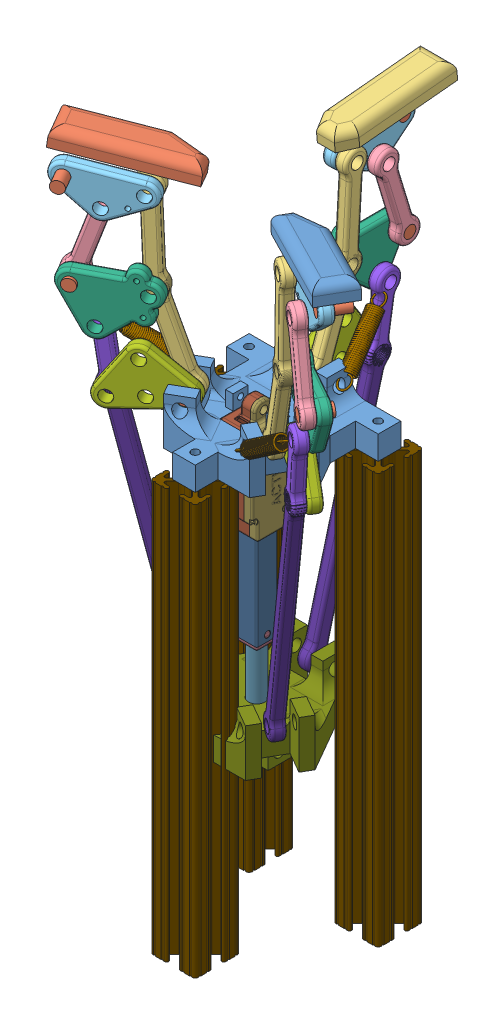
SolidWorks assembly Assem1, configuration Default. Lengths in mm.
Overall size (250.26 371.1 226.62).
54 component instances, 21 part files, 37 mates.
Components (placement in the parent):
- Base-1: Base [Default] at (29.1 37.1493 110.8136) size (84.55 26.4 78.57)
- Finger-1: Finger [Default] at (-55.3683 171.0063 18.6611) x (0.533631 -0.593126 -0.602859) z (-0.629379 -0.754665 0.185375) size (115.18 50.98 104.34)
  - Pin-2: Pin [Default] at (-28.0516 131.9417 56.9365) x (-0.391776 -0.247873 -0.886042) z (-0.883938 -0.165793 0.437227) size (6.6 14.85 6.6)
  - Pin-5: Pin [Default] at (35.7349 149.8083 61.935) x (0.798245 0.298021 0.523439) z (0.545563 0.010572 -0.838003) size (6.6 14.85 6.6)
  - 7.3mmLink-1: 7.3mmLink [Default] at (4.3719 127.2835 41.7035) x (0.803295 0.298106 0.515607) z (0.5381 0.007794 -0.842845) size (61.38 6.6 13.2)
  - 6mmLink-3: 6mmLink [Default] at (-36.8945 113.7346 26.1461) x (0.325014 0.234869 0.91608) z (0.910604 0.183752 -0.370183) size (53.43 6.6 13.2)
  - 7.3mmLink-2: 7.3mmLink [Default] at (-26.5117 113.5278 7.6718) x (0.61862 0.283769 0.732656) z (0.743064 0.091669 -0.662913) size (61.38 6.6 13.2)
  - TriLink3-3: TriLink3 [Default] at (-38.0213 120.0229 24.1342) x (0.965908 0.258866 0.003339) z (0.043091 -0.148042 -0.988042) size (41.14 6.6 31.73)
  - TriLink2-6: TriLink2 [Default] at (-5.9664 136.3894 72.3925) x (0.88404 0.294986 0.362569) z (0.391545 -0.04372 -0.91912) size (35.81 6.6 41.11)
  - TriLink1-5: TriLink1 [Default] at (11.5068 128.7631 61.1059) x (-0.06577 -0.176206 -0.982154) z (0.964629 0.240582 -0.107758) size (37.33 6.6 37.28)
  - Pin-6: Pin [Default] at (-62.2438 123.5843 18.9947) x (0.925135 0.287468 0.247965) z (0.280996 -0.07931 -0.956426) size (6.6 14.85 6.6)
  - 5mmLink-4: 5mmLink [Default] at (-3.3761 129.6337 69.0864) x (0.690224 0.29155 0.662261) z (0.677071 0.062661 -0.733245) size (46.2 6.6 13.2)
  - 9654K127_STEEL EXTENSION SPRING-1: 9654K127_STEEL EXTENSION SPRING [9654K127] at (22.3126 122.661 67.567) size (44.45 7.99 8.44)
- Finger-2: Finger [Default] at (1.5805 170.9978 213.2297) x (-0.790306 -0.59104 -0.161516) z (0.473443 -0.756402 0.45134) size (115.18 50.98 104.34)
  - Pin-2: Pin [Default] at (-28.0516 131.9417 56.9365) x (-0.391776 -0.247873 -0.886042) z (-0.883938 -0.165793 0.437227) size (6.6 14.85 6.6)
  - Pin-5: Pin [Default] at (35.7349 149.8083 61.935) x (0.798245 0.298021 0.523439) z (0.545563 0.010572 -0.838003) size (6.6 14.85 6.6)
  - 7.3mmLink-1: 7.3mmLink [Default] at (4.3719 127.2835 41.7035) x (0.803295 0.298106 0.515607) z (0.5381 0.007794 -0.842845) size (61.38 6.6 13.2)
  - 6mmLink-3: 6mmLink [Default] at (-36.8945 113.7346 26.1461) x (0.325014 0.234869 0.91608) z (0.910604 0.183752 -0.370183) size (53.43 6.6 13.2)
  - 7.3mmLink-2: 7.3mmLink [Default] at (-26.5117 113.5278 7.6718) x (0.61862 0.283769 0.732656) z (0.743064 0.091669 -0.662913) size (61.38 6.6 13.2)
  - TriLink3-3: TriLink3 [Default] at (-38.0213 120.0229 24.1342) x (0.965908 0.258866 0.003339) z (0.043091 -0.148042 -0.988042) size (41.14 6.6 31.73)
  - TriLink2-6: TriLink2 [Default] at (-5.9664 136.3894 72.3925) x (0.88404 0.294986 0.362569) z (0.391545 -0.04372 -0.91912) size (35.81 6.6 41.11)
  - TriLink1-5: TriLink1 [Default] at (11.5068 128.7631 61.1059) x (-0.06577 -0.176206 -0.982154) z (0.964629 0.240582 -0.107758) size (37.33 6.6 37.28)
  - Pin-6: Pin [Default] at (-62.2438 123.5843 18.9947) x (0.925135 0.287468 0.247965) z (0.280996 -0.07931 -0.956426) size (6.6 14.85 6.6)
  - 5mmLink-4: 5mmLink [Default] at (-3.3761 129.6337 69.0864) x (0.690224 0.29155 0.662261) z (0.677071 0.062661 -0.733245) size (46.2 6.6 13.2)
  - 9654K127_STEEL EXTENSION SPRING-1: 9654K127_STEEL EXTENSION SPRING [9654K127] at (22.3126 122.661 67.567) size (44.45 7.99 8.44)
- Finger-3: Finger [Default] at (140.3266 170.905 65.9303) x (0.255276 -0.574797 0.777459) z (0.15415 -0.769619 -0.619616) size (115.18 50.98 104.34)
  - Pin-2: Pin [Default] at (-28.0516 131.9417 56.9365) x (-0.391776 -0.247873 -0.886042) z (-0.883938 -0.165793 0.437227) size (6.6 14.85 6.6)
  - Pin-5: Pin [Default] at (35.7349 149.8083 61.935) x (0.798245 0.298021 0.523439) z (0.545563 0.010572 -0.838003) size (6.6 14.85 6.6)
  - 7.3mmLink-1: 7.3mmLink [Default] at (4.3719 127.2835 41.7035) x (0.803295 0.298106 0.515607) z (0.5381 0.007794 -0.842845) size (61.38 6.6 13.2)
  - 6mmLink-3: 6mmLink [Default] at (-36.8945 113.7346 26.1461) x (0.325014 0.234869 0.91608) z (0.910604 0.183752 -0.370183) size (53.43 6.6 13.2)
  - 7.3mmLink-2: 7.3mmLink [Default] at (-26.5117 113.5278 7.6718) x (0.61862 0.283769 0.732656) z (0.743064 0.091669 -0.662913) size (61.38 6.6 13.2)
  - TriLink3-3: TriLink3 [Default] at (-38.0213 120.0229 24.1342) x (0.965908 0.258866 0.003339) z (0.043091 -0.148042 -0.988042) size (41.14 6.6 31.73)
  - TriLink2-6: TriLink2 [Default] at (-5.9664 136.3894 72.3925) x (0.88404 0.294986 0.362569) z (0.391545 -0.04372 -0.91912) size (35.81 6.6 41.11)
  - TriLink1-5: TriLink1 [Default] at (11.5068 128.7631 61.1059) x (-0.06577 -0.176206 -0.982154) z (0.964629 0.240582 -0.107758) size (37.33 6.6 37.28)
  - Pin-6: Pin [Default] at (-62.2438 123.5843 18.9947) x (0.925135 0.287468 0.247965) z (0.280996 -0.07931 -0.956426) size (6.6 14.85 6.6)
  - 5mmLink-4: 5mmLink [Default] at (-3.3761 129.6337 69.0864) x (0.690224 0.29155 0.662261) z (0.677071 0.062661 -0.733245) size (46.2 6.6 13.2)
  - 9654K127_STEEL EXTENSION SPRING-1: 9654K127_STEEL EXTENSION SPRING [9654K127] at (22.3126 122.661 67.567) size (44.45 7.99 8.44)
- LA1-1: LA1 [Default] at (27.9949 18.3736 107.6457) size (20.03 168.75 20.21) (flexible)
  - EXTENSION_10404_50MM-1: EXTENSION_10404_50MM [Default] at (0.8849 -9.7956 -4.9621) size (12 60 12)
  - CLAMSHELL_BOT_10654-1: CLAMSHELL_BOT_10654 [Default] at (0.8849 36.6044 -13.4621) x (0 0 -1) z (0 -1 0) size (20 14.51 62.21)
  - CLAMSHELL_TOP_10653-1: CLAMSHELL_TOP_10653 [Default] at (0.8849 36.6044 -13.4621) x (0 0 -1) z (0 -1 0) size (20.21 11.32 62)
  - GUIDE_10429-1: GUIDE_10429 [Default] at (0.8849 -71.7956 -4.9621) x (0 0 -1) z (-1 0 0) size (12 7.21 12)
  - SHAFT_10409_50MM2-1: SHAFT_10409_50MM2 [Default] at (0.8849 -57.1489 -4.9621) x (-0.424332 0 0.905507) z (-0.905507 0 -0.424332) size (8.95 58 8.95)
  - PLUG_10428-1: PLUG_10428 [Default] at (0.8849 -122.1489 -4.9621) x (-1 0 0) z (0 0 1) size (9 14 9.15)
- BottomPLate-1: BottomPLate [Default] at (28.8798 -98.7629 111.1366) size (76.21 39.1 66)
- 14mmLink-1: 14mmLink [Default] at (36.379 -58.906 69.3197) x (0 0.966466 -0.256796) z (0 0.256796 0.966466) size (147.31 6.6 13.2)
- 14mmLink-2: 14mmLink [Default] at (-0.1646 -58.8123 118.3646) x (-0.202668 0.972232 0.117011) z (-0.841977 -0.234021 0.486116) size (147.31 6.6 13.2)
- 14mmLink-3: 14mmLink [Default] at (59.7729 -58.823 115.2517) x (0.205037 0.971569 0.118378) z (0.841403 -0.236757 0.485784) size (147.31 6.6 13.2)
- 1010_9-1: 1010_9 [Default] at (65.0865 -301.6512 71.1817) x (1 0 0) z (0 -1 0) size (25.4 25.4 228.6)
- 1010_9-2: 1010_9 [Default] at (-6.8865 -301.6512 71.1817) x (1 0 0) z (0 -1 0) size (25.4 25.4 228.6)
- 1010_9-3: 1010_9 [Default] at (29.1 -301.6512 137.1817) x (1 0 0) z (0 -1 0) size (25.4 25.4 228.6)
- AngledEnd2-1: AngledEnd2 [Default] at (81.8626 162.7367 122.3471) x (0.5 0 -0.866025) z (0.860146 0.116327 0.496605) size (20 10 63.5)
- AngledEnd3-2: AngledEnd3 [Default] at (-24.0913 172.7398 118.6687) x (-0.5 0 -0.866025) z (-0.859868 0.119036 0.496445) size (20 10 63.5)
- AngledEnd-3: AngledEnd [Default] at (24.679 173.8434 24.7115) x (1 0 0) z (0 0.095388 -0.99544) size (20 10 63.5)
Mates (geometry in assembly coordinates):
- Concentric1: concentric anti-aligned: cylinder of Base-1 through (26.429 61.0488 154.4373) axis (-0.5 0 -0.866025) radius 3.3; cylinder of Finger-1/Pin-5 through (0.0107 61.0488 108.6794) axis (0.5 0 0.866025) radius 3.3
- Concentric2: concentric anti-aligned: cylinder of Base-1 through (79.4024 61.0488 71.9373) axis (-0.5 0 0.866025) radius 3.3; cylinder of Finger-2/Pin-5 through (51.5894 61.0488 120.1109) axis (0.5 0 -0.866025) radius 3.3
- Coincident2: coincident anti-aligned: plane of Base-1 through (52.4736 67.6488 105.3794) normal (-0.5 0 0.866025); plane of Finger-2/TriLink1-5 through (86.3878 55.6822 124.9597) normal (0.5 0 -0.866025)
- Concentric3: concentric aligned: cylinder of Base-1 through (67.2051 61.0488 71.4952) axis (-1 0 0) radius 3.3; cylinder of Finger-3/Pin-5 through (34.679 61.0488 71.4952) axis (-1 0 0) radius 3.3
- Coincident3: coincident anti-aligned: plane of Base-1 through (21.479 67.6488 78.0952) normal (1 0 0); plane of Finger-3/TriLink1-5 through (21.479 54.9978 39.0547) normal (-1 0 0)
- Concentric4: concentric aligned: cylinder of Base-1 through (45.0258 59.478 102.6836) axis (-1 0 0) radius 1.65; cylinder of LA1-1/CLAMSHELL_BOT_10654-1 through (32.8798 59.478 102.6836) axis (-1 0 0) radius 2.125
- Coincident5: coincident anti-aligned: plane of Base-1 through (19.8798 62.8308 106.8746) normal (1 0 0); plane of LA1-1/CLAMSHELL_BOT_10654-1 through (19.8798 54.978 114.1836) normal (-1 0 0)
- Parallel1: parallel aligned: plane of Base-1 through (19.8798 62.8308 98.4926) normal (0 0 -1); plane of LA1-1/CLAMSHELL_BOT_10654-1 through (19.8798 54.978 94.1836) normal (0 0 -1)
- Concentric5: concentric: cylinder of LA1-1/PLUG_10428-1 through (24.3798 -71.5568 102.6836) axis (1 0 0) radius 2.125; cylinder of BottomPLate-1 through (43.4086 -71.5568 102.6836) axis (-1 0 0) radius 1.65
- Parallel2: parallel aligned: plane of Base-1 through (5.2159 54.4488 130.8952) normal (0 0 1); plane of BottomPLate-1 through (4.9957 -81.2168 132.8941) normal (0 0 1)
- Concentric6: concentric anti-aligned: cylinder of BottomPLate-1 through (66.9849 -74.6168 73.4941) axis (-1 0 0) radius 3.3; cylinder of 14mmLink-1 through (28.079 -74.6168 73.4941) axis (1 0 0) radius 3.3
- Concentric7: concentric anti-aligned: cylinder of 14mmLink-1 through (28.079 54.9978 39.0547) axis (1 0 0) radius 3.3; circle of Finger-3/TriLink1-5
- Concentric8: concentric anti-aligned: cylinder of BottomPLate-1 through (26.2088 -74.6168 156.4362) axis (-0.5 0 -0.866025) radius 3.3; cylinder of 14mmLink-2 through (-1.0201 -74.6168 109.2745) axis (0.5 0 0.866025) radius 3.3
- Concentric9: concentric anti-aligned: cylinder of 14mmLink-2 through (-28.2003 55.7711 124.967) axis (0.5 0 0.866025) radius 3.3; cylinder of Finger-1/TriLink1-5 through (-21.6003 55.7711 136.3985) axis (-0.5 0 -0.866025) radius 3.3
- Concentric10: concentric anti-aligned: cylinder of BottomPLate-1 through (79.1822 -74.6168 73.9362) axis (-0.5 0 0.866025) radius 3.3; cylinder of 14mmLink-3 through (52.2898 -74.6168 120.5153) axis (0.5 0 -0.866025) radius 3.3
- Distance1: distance = 6.35 mm: plane of BottomPLate-1 through (19.5298 -68.204 106.8746) normal (1 0 0); plane of LA1-1/PLUG_10428-1 through (25.7747 -72.4525 100.44) normal (-1 0 0)
- Concentric11: concentric anti-aligned: cylinder of Base-1 through (65.0865 72.2297 71.1817) axis (0 -1 0) radius 2.1793; cylinder of 1010_9-1 through (65.0865 -187.3512 71.1817) axis (0 1 0) radius 2.6035
- Coincident12: coincident anti-aligned: plane of Base-1 through (29.1 41.2488 106.2636) normal (0 -1 0); plane of 1010_9-1 through (54.4947 41.2488 60.5899) normal (0 1 0)
- Concentric12: concentric anti-aligned: cylinder of Base-1 through (-6.8865 72.2297 71.1817) axis (0 -1 0) radius 2.1793; cylinder of 1010_9-2 through (-6.8865 -187.3512 71.1817) axis (0 1 0) radius 2.6035
- Coincident13: coincident anti-aligned: plane of Base-1 through (29.1 41.2488 106.2636) normal (0 -1 0); plane of 1010_9-2 through (-17.4783 41.2488 60.5899) normal (0 1 0)
- Concentric13: concentric anti-aligned: circle of Base-1; cylinder of 1010_9-3 through (29.1 -187.3512 137.1817) axis (0 1 0) radius 2.6035
- Coincident14: coincident anti-aligned: plane of Base-1 through (29.1 41.2488 106.2636) normal (0 -1 0); plane of 1010_9-3 through (18.5082 41.2488 126.5899) normal (0 1 0)
- Concentric14: concentric anti-aligned: cylinder of 14mmLink-3 through (79.7878 55.6822 136.3913) axis (0.5 0 -0.866025) radius 3.3; cylinder of Finger-2/TriLink1-5 through (86.3878 55.6822 124.9597) axis (-0.5 0 0.866025) radius 3.3
- Coincident15: coincident anti-aligned: plane of Finger-2/TriLink1-5 through (83.0878 55.6822 130.6755) normal (-0.5 0 0.866025); plane of 14mmLink-3 through (48.1435 -64.6013 110.5004) normal (0.5 0 -0.866025)
- Coincident16: coincident anti-aligned: plane of Finger-1/TriLink1-5 through (-24.9003 55.7711 130.6828) normal (-0.5 0 -0.866025); plane of 14mmLink-2 through (9.7506 -64.6256 110.6771) normal (0.5 0 0.866025)
- Coincident17: coincident anti-aligned: plane of Finger-3/TriLink1-5 through (28.079 54.9978 39.0547) normal (1 0 0); plane of 14mmLink-1 through (28.079 -69.934 61.1527) normal (-1 0 0)
- Coincident25: coincident anti-aligned: plane of Finger-2/TriLink3-3 through (97.8286 165.3422 139.1861) normal (-0.100742 0.993211 -0.058164); plane of AngledEnd2-1 through (81.8626 162.7367 122.3471) normal (0.100742 -0.993211 0.058164)
- Distance2: distance = 10 mm aligned: plane of Finger-2/TriLink3-3 through (101.7934 158.787 133.8542) normal (0.5 0 -0.866025); plane of AngledEnd2-1 through (113.1648 176.3622 128.8725) normal (0.5 0 -0.866025)
- Coincident26: coincident anti-aligned: plane of Finger-1/TriLink3-3 through (-39.3819 165.4771 139.0437) normal (0.103089 0.99289 -0.059518); plane of AngledEnd3-2 through (-25.1222 162.8109 119.2639) normal (-0.103089 -0.99289 0.059518)
- Coincident28: coincident anti-aligned: plane of Finger-1/TriLink3-3 through (-40.0623 158.924 139.4366) normal (-0.5 0 -0.866025); plane of AngledEnd3-2 through (7.1786 159.0315 112.162) normal (0.5 0 0.866025)
- Coincident29: coincident anti-aligned: plane of Base-1 through (-5.7051 67.6488 111.9794) normal (0.5 0 0.866025); plane of Finger-1/7.3mmLink-1 through (-19.8398 96.1011 120.1401) normal (-0.5 0 -0.866025)
- Coincident30: coincident anti-aligned: plane of Finger-3/TriLink3-3 through (28.079 164.2751 19.7282) normal (0 0.99544 0.095388); plane of AngledEnd-3 through (24.679 163.889 23.7576) normal (0 -0.99544 -0.095388)
- Coincident31: coincident aligned: plane of AngledEnd-3 through (34.679 166.5045 -3.5372) normal (1 0 0); plane of Finger-3/7.3mmLink-2 through (34.679 146.207 42.2098) normal (1 0 0)
- Tangent7: tangent aligned: cylinder of Finger-3/7.3mmLink-2 through (34.679 154.507 52.4738) axis (-1 0 0) radius 6.6; plane of AngledEnd-3 through (19.679 160.4474 59.6732) normal (0 -0.095388 0.99544)
- Tangent8: tangent: cylinder of Finger-2/TriLink3-3 through (69.6545 154.8868 122.9198) axis (0.5 0 -0.866025) radius 3.3; line of AngledEnd2-1 through (73.9554 165.9447 106.2349) axis (0.100742 -0.993211 0.058164)
- Tangent9: tangent: cylinder of Finger-1/7.3mmLink-2 through (-14.5326 154.933 117.076) axis (0.5 0 0.866025) radius 3.3; line of AngledEnd3-2 through (-17.7147 161.0932 103.4402) axis (0.103089 0.99289 -0.059518)
- Concentric15: concentric anti-aligned: cylinder of LA1-1/SHAFT_10409_50MM2-1 through (28.8798 -38.7753 102.6836) axis (0 -1 0) radius 4.475; cylinder of BottomPLate-1 through (28.8798 -94.4168 102.6836) axis (0 1 0) radius 4.6355
